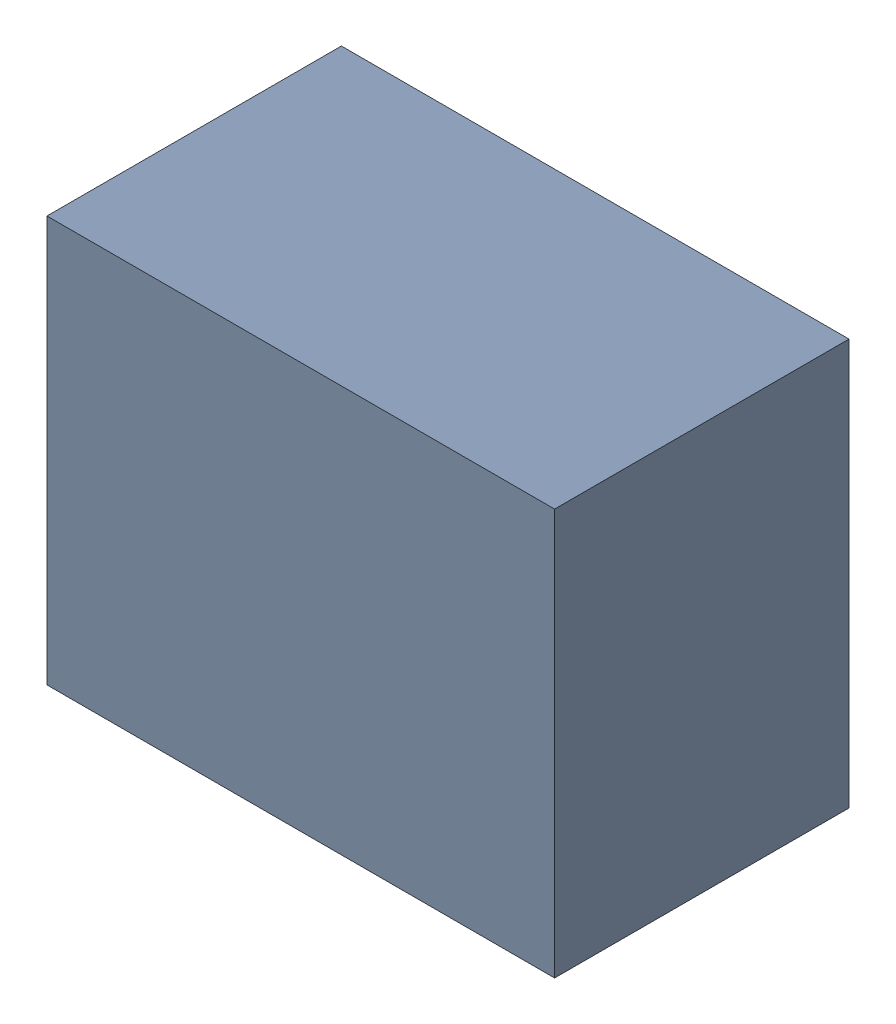
SolidWorks assembly U1, configuration Default. Lengths in mm.
Overall size (1 0.8 0.58).
2 component instances, 1 part files, 0 mates.
Components (placement in the parent):
- 810372112-1: 810372112 [Default] at (110.75 8.15 0.5) size (1 0.8 0.58)
  - Extruded_43-1: Extruded_43 [Default] at origin size (1 0.8 0.58)
